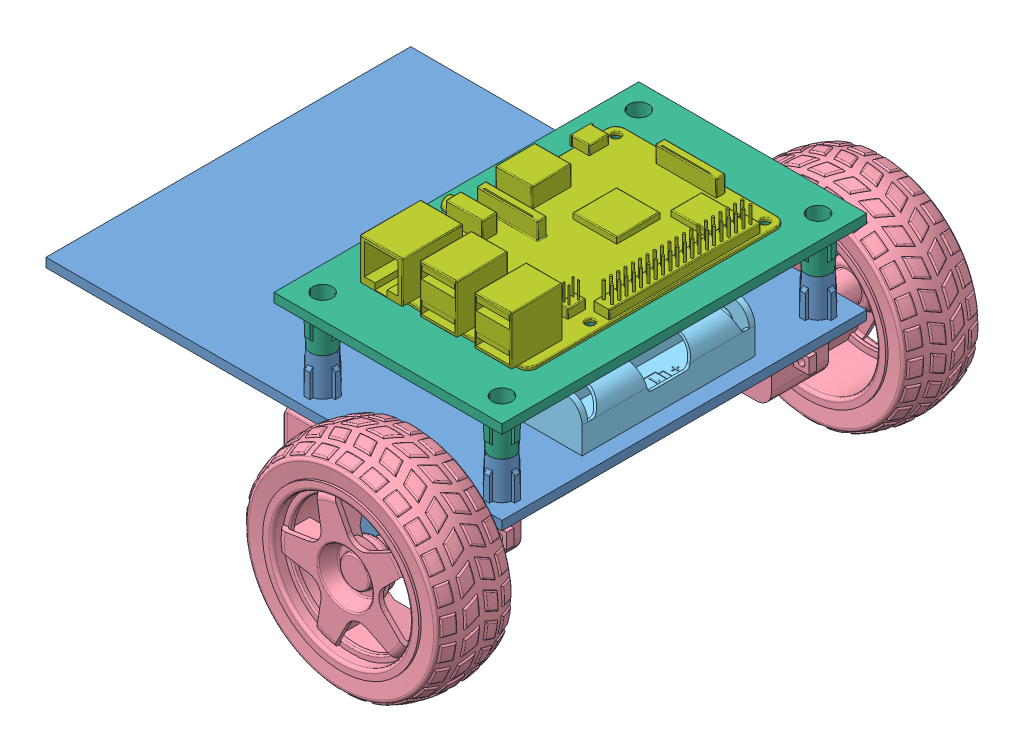
SolidWorks assembly Assem1, configuration Default. Lengths in mm.
Overall size (160.78 93.48 178.6).
14 component instances, 8 part files, 3 mates.
Components (placement in the parent):
- body-final-1: body-final [Default] at (-13.6354 -10.9354 6.4951) size (160.78 93.48 178.6)
  - main2-1: main2 [Default] at (1.1724 18.4599 -13.16) size (160.78 69.55 178.6)
    - main1-1: main1 [Default] at (-18.5074 6.649 48.7257) size (160.78 69.55 178.6)
      - Part1-1: Part1 [Default] at (-6.1553 78.7696 167.0022) size (150 37.55 124)
      - caster-1: caster [Default] at (47.2378 72.3089 131.4385) x (0 0 -1) z (-1 0 0) size (44 45 28)
        - cup-1: cup [Default] at (19.4271 17.5393 31.8931) size (44 38.22 28)
        - sphere-1: sphere [Default] at (14.2695 30.5393 38.0085) size (16 16 16)
      - motor+wheel+pad-1: motor+wheel+pad [Default] at (-23.0627 -16.2309 210.4693) x (0 0 -1) z (1 0 0) size (57.2 68.99 89.08)
      - motor+wheel+pad-2: motor+wheel+pad [Default] at (-23.0627 151.4701 3.5351) x (0 0 1) z (1 0 0) size (57.2 68.99 89.08)
    - User Library-R6_AA_UM3-1_5V_holder4AA-2: User Library-R6_AA_UM3-1_5V_holder4AA [4AA] at (89.3972 88.4185 155.728) x (0 0 1) z (0 1 0) size (59.56 61.47 15.11)
  - lvl2+rasp-2: lvl2+rasp [Default] at (129.0378 55.5535 233.9168) x (-1 0 0) z (0 0 -1) size (75 39.81 120)
    - lvl2-1: lvl2 [Default] at (2.5282 78.8169 151.3489) x (1 0 0) z (0 0 -1) size (75 22.75 120)
    - Raspberrypimodel-2: Raspberrypimodel [Default] at (37.0282 78.8825 92.3489) x (0 0 -1) z (1 0 0) size (87.5 17 58)
- L298N-1: L298N [Predeterminado] at (98.4174 92.943 170.363) x (1 0 0) z (0 0 -1) size (43 25 43)
Mates (geometry in assembly coordinates):
- Coincident1: coincident: plane of body-final-1/main2-1/main1-1/Part1-1 through (-37.1258 92.943 209.063) normal (0 -1 0); plane of L298N-1 through (98.4174 92.943 168.9162) normal (0 1 0)
- Distance1: distance = 15 mm: line of body-final-1/main2-1/main1-1/Part1-1 through (112.8742 95.943 209.063) axis (0 0 -1); line of L298N-1 through (98.4174 91.943 170.363) axis (0 0 -1)
- Distance2: distance = 19.5 mm: line of body-final-1/main2-1/main1-1/motor+wheel+pad-2 through (95.3742 92.943 107.863) axis (-1 0 0); line of L298N-1 through (98.4174 92.943 127.363) axis (-1 0 0)
